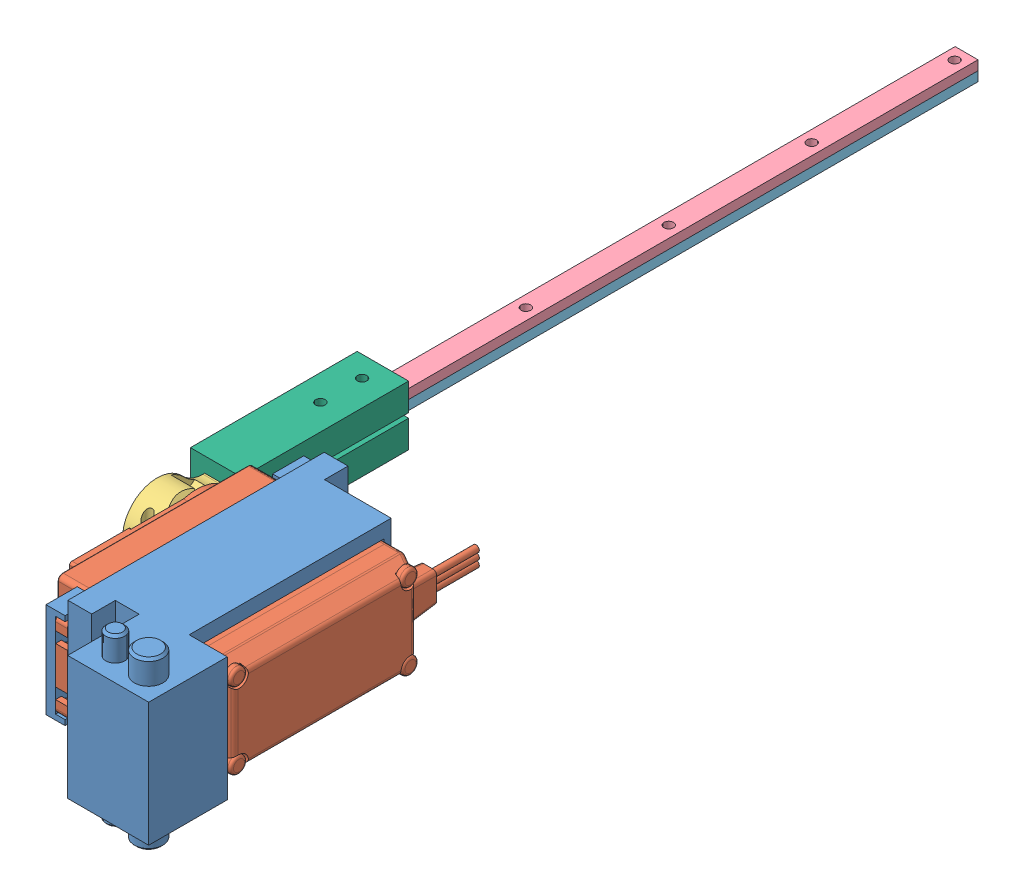
SolidWorks assembly servomech, configuration Default. Lengths in mm.
Overall size (48.65 35 214.9).
6 component instances, 6 part files, 15 mates.
Components (placement in the parent):
- Single Servo assembly v21-1: Single Servo assembly v21 [Default] at (49.7164 35.1874 34.3477) size (31.5 35 64.05)
- Servo-1: Servo [Default] at (36.6438 35.1874 43.9482) x (0 0 -1) z (0 1 0) size (63.95 43.45 20)
- Servo Horn v1-1: Servo Horn v1 [Default] at (-2.9962 35.1874 33.4982) x (0 0 -1) z (-1 0 0) size (34.33 14.5 6)
- Component2-1: Component2 [Default] at (49.9664 34.9874 34.3477) size (4.8 2 140)
- Component3-1: Component3 [Default] at (49.9664 35.1874 34.3477) size (4.8 2 140)
- Component1-2: Component1 [Default] at (49.9664 35.1874 34.3477) size (10.8 12.5 35)
Mates (geometry in assembly coordinates):
- Coincident1: coincident: plane of assembly; plane of Single Servo assembly v21-1 through (36.6438 35.1874 72.6482) normal (1 0 0); plane of Servo-1 through (36.6438 35.1874 43.9482) normal (1 0 0)
- Width1: width: plane of assembly; plane of assembly; plane of Single Servo assembly v21-1 through (9.6438 45.1874 64.3982) normal (0 0 -1); plane of Single Servo assembly v21-1 through (9.6438 45.1874 23.4982) normal (0 0 1); plane of Servo-1 through (9.6438 45.1874 64.3982) normal (0 0 1); plane of Servo-1 through (9.6438 45.1874 23.4982) normal (0 0 -1)
- Coincident2: coincident: plane of assembly; plane of Single Servo assembly v21-1 through (9.6438 25.1874 64.3982) normal (0 1 0); plane of Servo-1 through (9.6438 25.1874 64.3982) normal (0 -1 0)
- Concentric1: concentric aligned: circle of Servo-1; circle of Servo Horn v1-1
- Coincident3: coincident anti-aligned: plane of Servo-1 through (-6.7962 35.1874 33.4982) normal (-1 0 0); plane of Servo Horn v1-1 through (-6.7962 35.1874 33.4982) normal (1 0 0)
- Coincident5: coincident anti-aligned: plane of Servo Horn v1-1 through (-2.9962 35.1874 33.4982) normal (1 0 0); plane of Component1-2 through (-2.9962 35.9374 3.4982) normal (-1 0 0)
- Concentric2: concentric aligned: circle of Servo Horn v1-1; circle of Component1-2
- Coincident7: coincident anti-aligned: plane of Component3-1 through (-6.5962 33.0874 -64.0018) normal (0 -1 0); plane of Component1-2 through (-6.5962 33.0874 -2.7518) normal (0 1 0)
- Concentric3: concentric anti-aligned: circle of Component3-1; circle of Component1-2
- Coincident10: coincident anti-aligned: plane of Component2-1 through (-6.5962 35.0874 -64.0018) normal (0 -1 0); plane of Component3-1 through (-6.5962 35.0874 -64.0018) normal (0 1 0)
- Concentric4: concentric aligned: circle of Component2-1; circle of Component1-2
- Concentric5: concentric aligned: circle of Component2-1; circle of Component3-1
- Coincident15: coincident anti-aligned: plane of Component3-1 through (-8.9962 33.0874 -134.0018) normal (-1 0 0); plane of Component1-2 through (-8.9962 33.9374 3.4982) normal (1 0 0)
- Coincident16: coincident anti-aligned: plane of Servo Horn v1-1 through (-8.9962 32.0874 33.4982) normal (0 -1 0); plane of Component1-2 through (-8.9962 32.0874 -11.5018) normal (0 1 0)
- Parallel1: parallel: plane of assembly; plane of Single Servo assembly v21-1 through (12.1438 48.1874 19.9732) normal (0 1 0); plane of Component2-1 through (-6.5962 37.0874 -64.0018) normal (0 1 0)
